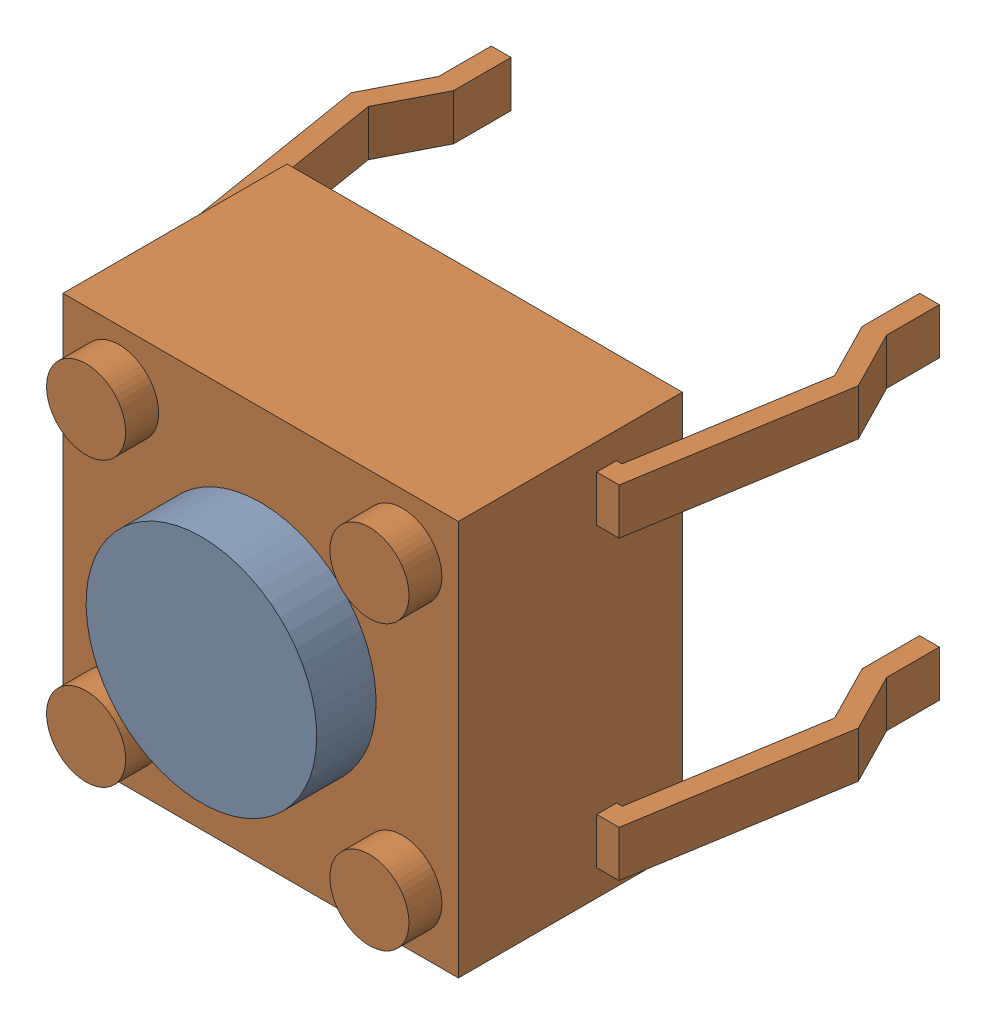
SolidWorks assembly Kanaloa_v2.0.0_Loko_1, configuration Default. Lengths in mm.
Overall size (7.7 6 7.8).
3 component instances, 2 part files, 0 mates.
Components (placement in the parent):
- OMRON-B3F_1000-1: OMRON-B3F_1000 [Default] at (90.1046 75.7682 0) x (1 0 0) z (0 -1 0) size (7.7 7.8 6)
  - OMRON-B3F_1000_B3F_1000_BUTTON-1: OMRON-B3F_1000_B3F_1000_BUTTON [Default] at (0 4.3 0) x (-1 0 0) z (0 0 -1) size (3.5 1 3.5)
  - OMRON-B3F_1000_B3F_1000_BASE-1: OMRON-B3F_1000_B3F_1000_BASE [Default] at origin size (7.7 7.4 6)
